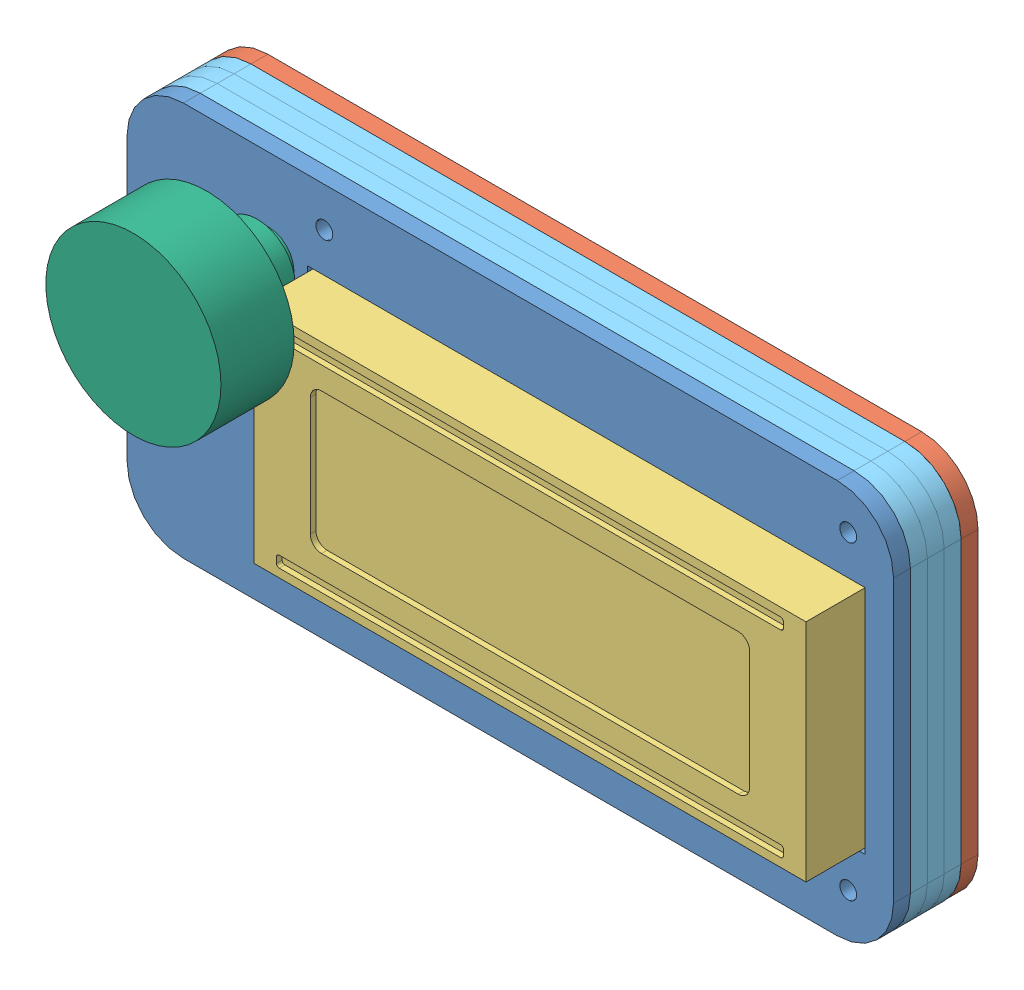
SolidWorks assembly Panel, configuration Default. Lengths in mm.
Overall size (136.06 70 39).
8 component instances, 6 part files, 20 mates.
Components (placement in the parent):
- Panel-1: Panel [Default] at (36.5683 121.8199 -7) x (-1 0 0) z (0 -1 0) size (136.06 3 70)
- Panel back-1: Panel back [Default] at (36.5683 121.8199 -19) x (-1 0 0) z (0 0 -1) size (136.06 70 3)
- lcd-1: lcd [Default] at (-38 75.2988 -17) x (1 0 0) z (0 -1 0) size (98 15 60)
- Part2^Panel-1: Part2^Panel [Default] at (94.6769 215.7132 -12) x (-1 0 0) z (0 0 -1) size (123.2 62.19 3)
- Part1^Panel-1: Part1^Panel [Default] at (0 0 -10) x (-1 0 0) z (0 0 -1) size (136.06 70 3) (virtual)
- Part1^Panel-2: Part1^Panel [Default] at (0 0 -13) x (-1 0 0) z (0 0 -1) size (136.06 70 3) (virtual)
- Part1^Panel-3: Part1^Panel [Default] at (0 0 -16) x (-1 0 0) z (0 0 -1) size (136.06 70 3) (virtual)
- Part3^Panel-2: Part3^Panel [Default] at (0 0 -12) size (31.09 31.09 29) (virtual)
Mates (geometry in assembly coordinates):
- Coincidente1: coincident anti-aligned: plane of Panel-1 through (58.1909 88.3774 85.8438) normal (0 1 0); plane of lcd-1 through (-3.2409 88.3774 128.3649) normal (0 -1 0)
- Concêntrico5: concentric aligned: cylinder of Panel-1 through (95.5 136.7988 -10) axis (0 0 1) radius 1.5; cylinder of Panel back-1 through (95.5 136.7988 -22) axis (0 0 1) radius 1.3
- Concentric4: concentric anti-aligned: circle of Panel-1; circle of lcd-1
- Concentric5: concentric anti-aligned: circle of Panel-1; circle of lcd-1
- Coincident9: coincident anti-aligned: plane of Panel-1 through (36.5683 121.8199 -10) normal (0 0 -1); plane of lcd-1 through (98 79.2988 -10) normal (0 0 1)
- Concentric6: concentric anti-aligned: cylinder of Panel back-1 through (2.5 136.7988 -22) axis (0 0 1) radius 1.5; cylinder of lcd-1 through (2.5 136.7988 -10) axis (0 0 -1) radius 1.75
- Coincident10: coincident anti-aligned: plane of Panel-1 through (36.5683 121.8199 -10) normal (0 0 -1); plane of Part1^Panel-1 through (93.5366 83.7988 -10) normal (0 0 1)
- Concentric7: concentric aligned: cylinder of Panel-1 through (-22.5267 133.7988 -10) axis (0 0 1) radius 10; cylinder of Part1^Panel-1 through (-22.5267 133.7988 -13) axis (0 0 1) radius 10
- Coincident12: coincident aligned: plane of lcd-1 through (98 139.2988 -10) normal (1 0 0); plane of Part2^Panel-1 through (98 215.7132 -15) normal (1 0 0)
- Coincident13: coincident anti-aligned: plane of lcd-1 through (98 79.2988 -12) normal (0 0 -1); plane of Part2^Panel-1 through (94.6769 215.7132 -12) normal (0 0 1)
- Coincident14: coincident aligned: plane of lcd-1 through (98 79.2988 -10) normal (0 -1 0); plane of Part2^Panel-1 through (94.6769 79.2988 -15) normal (0 -1 0)
- Parallel1: parallel anti-aligned: plane of lcd-1 through (98 79.2988 -10) normal (0 -1 0); plane of Part1^Panel-1 through (98 79.1138 -13) normal (0 1 0)
- Coincident16: coincident anti-aligned: plane of Part1^Panel-1 through (93.5366 83.7988 -13) normal (0 0 -1); plane of Part1^Panel-2 through (93.5366 83.7988 -13) normal (0 0 1)
- Concentric8: concentric aligned: cylinder of Panel-1 through (-22.5267 133.7988 -10) axis (0 0 1) radius 10; cylinder of Part1^Panel-2 through (-22.5267 133.7988 -16) axis (0 0 1) radius 10
- Parallel2: parallel anti-aligned: plane of lcd-1 through (98 79.2988 -10) normal (0 -1 0); plane of Part1^Panel-2 through (98 79.1138 -16) normal (0 1 0)
- Coincident17: coincident anti-aligned: plane of Part1^Panel-2 through (93.5366 83.7988 -16) normal (0 0 -1); plane of Part1^Panel-3 through (93.5366 83.7988 -16) normal (0 0 1)
- Concentric9: concentric aligned: cylinder of Panel-1 through (-22.5267 133.7988 -10) axis (0 0 1) radius 10; cylinder of Part1^Panel-3 through (-22.5267 133.7988 -19) axis (0 0 1) radius 10
- Parallel3: parallel anti-aligned: plane of lcd-1 through (98 79.2988 -10) normal (0 -1 0); plane of Part1^Panel-3 through (98 79.1138 -19) normal (0 1 0)
- Coincident18: coincident aligned: plane of Panel back-1 through (103.5366 133.7988 -22) normal (1 0 0); plane of Part1^Panel-3 through (103.5366 133.7988 -19) normal (1 0 0)
- Coincident19: coincident anti-aligned: plane of Panel back-1 through (-22.5267 133.7988 -19) normal (0 0 1); plane of Part1^Panel-3 through (93.5366 83.7988 -19) normal (0 0 -1)
